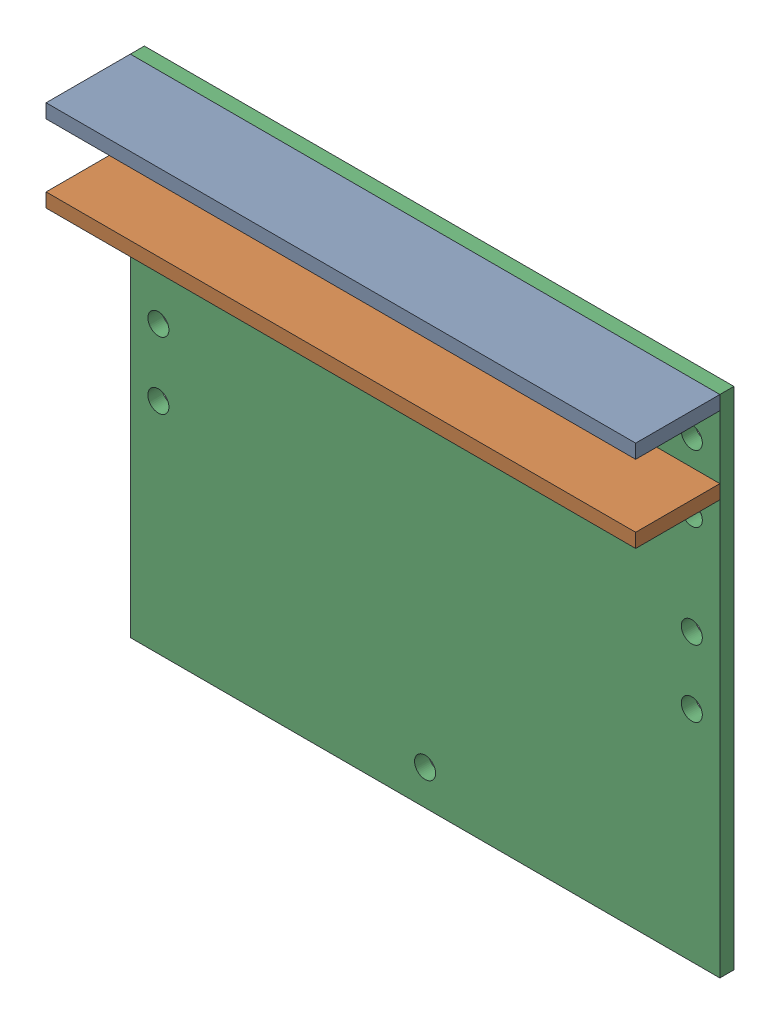
SolidWorks assembly chamber wall ass, configuration Default. Lengths in mm.
Overall size (533.4 457.2 88.9).
3 component instances, 2 part files, 0 mates.
Components (placement in the parent):
- Chamber wall flange-1: Chamber wall flange [Default] at (-328.7125 182.3769 97.008) size (533.4 12.7 76.2)
- Chamber wall flange-2: Chamber wall flange [Default] at (-328.7125 112.5269 97.008) size (533.4 12.7 76.2)
- Chamber Walls-1: Chamber Walls [Default] at (-390.878 195.0769 43.2718) size (533.4 457.2 12.7)
